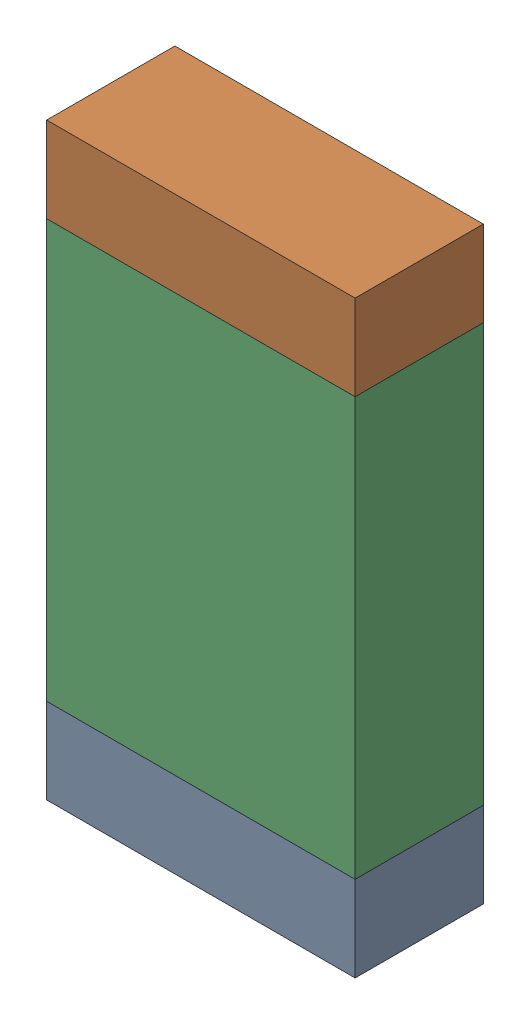
SolidWorks assembly R15, configuration Default. Lengths in mm.
Overall size (0.55 1.05 0.23).
6 component instances, 2 part files, 0 mates.
Components (placement in the parent):
- 822503136-1: 822503136 [Default] at (21.1652 16.45 0.0254) size (0.55 0.15 0.23)
  - Extruded_13-1: Extruded_13 [Default] at origin size (0.55 0.15 0.23)
- 822503136-2: 822503136 [Default] at (21.1652 17.3477 0.0254) size (0.55 0.15 0.23)
  - Extruded_13-1: Extruded_13 [Default] at origin size (0.55 0.15 0.23)
- 822503272-1: 822503272 [Default] at (21.1652 16.8988 0.0254) size (0.55 0.75 0.23)
  - Extruded_14-1: Extruded_14 [Default] at origin size (0.55 0.75 0.23)
